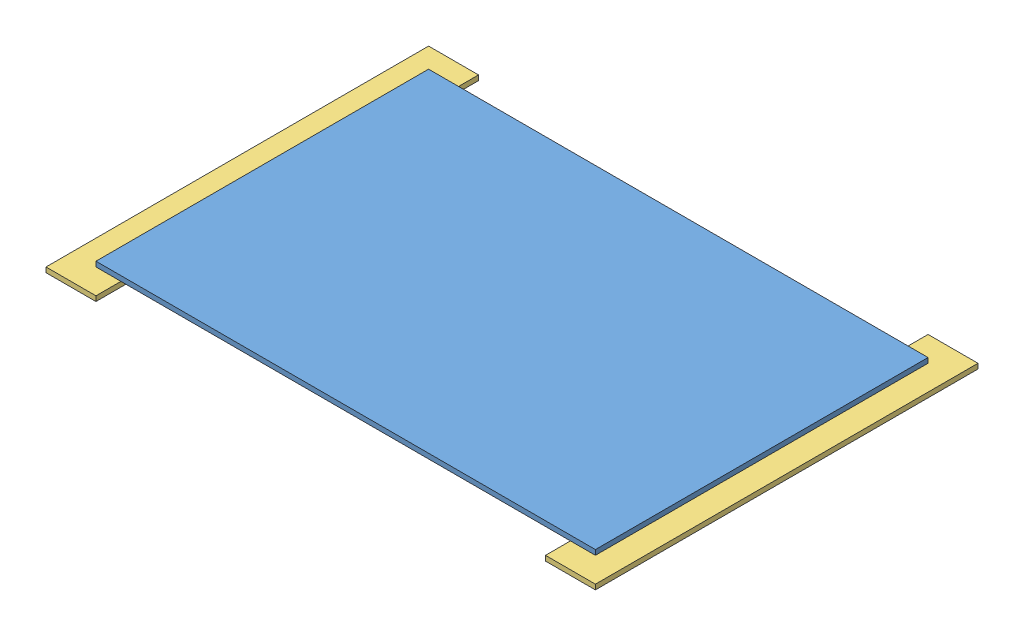
SolidWorks assembly Terrain_9_Partie_5, configuration Default. Lengths in mm.
Overall size (1100 20 766).
4 component instances, 3 part files, 9 mates.
Components (placement in the parent):
- planche_1000x666x10-1: planche_1000x666x10 [Default] at (-501.182 145.1843 231.5907) size (1000 10 666)
- planche_900x100x10-1: planche_900x100x10 [Default] at (-451.182 135.1843 -51.4093) size (900 10 100)
- planche_766x100x10-1: planche_766x100x10 [Default] at (548.818 135.1843 281.5907) x (0 0 -1) z (1 0 0) size (766 10 100)
- planche_766x100x10-2: planche_766x100x10 [Default] at (-451.182 135.1843 281.5907) x (0 0 -1) z (1 0 0) size (766 10 100)
Mates (geometry in assembly coordinates):
- Coïncidente1: coincident anti-aligned: plane of planche_1000x666x10-1 through (-501.182 145.1843 -434.4093) normal (0 -1 0); plane of planche_900x100x10-1 through (-451.182 145.1843 -151.4093) normal (0 1 0)
- Distance1: distance = 50 mm aligned: plane of planche_900x100x10-1 through (448.818 145.1843 -51.4093) normal (1 0 0); plane of planche_1000x666x10-1 through (498.818 155.1843 231.5907) normal (1 0 0)
- Distance4: distance = 383 mm anti-aligned: plane of planche_900x100x10-1 through (-451.182 145.1843 -151.4093) normal (0 0 -1); plane of planche_1000x666x10-1 through (-501.182 155.1843 231.5907) normal (0 0 1)
- Coïncidente2: coincident anti-aligned: plane of planche_1000x666x10-1 through (-501.182 145.1843 -434.4093) normal (0 -1 0); plane of ? through (448.818 145.1843 217.9054) normal (0 1 0)
- Coïncidente3: coincident anti-aligned: plane of planche_1000x666x10-1 through (-501.182 145.1843 -434.4093) normal (0 -1 0); plane of planche_766x100x10-2 through (-551.182 145.1843 281.5907) normal (0 1 0)
- Coïncidente4: coincident anti-aligned: plane of planche_900x100x10-1 through (448.818 145.1843 -51.4093) normal (1 0 0); plane of ? through (448.818 145.1843 217.9054) normal (-1 0 0)
- Coïncidente5: coincident anti-aligned: plane of planche_900x100x10-1 through (-451.182 145.1843 -51.4093) normal (-1 0 0); plane of planche_766x100x10-2 through (-451.182 145.1843 281.5907) normal (1 0 0)
- Distance5: distance = 50 mm aligned: plane of planche_766x100x10-2 through (-451.182 145.1843 281.5907) normal (0 0 1); plane of planche_1000x666x10-1 through (-501.182 155.1843 231.5907) normal (0 0 1)
- Coïncidente7: coincident aligned: plane of ? through (548.818 145.1843 217.9054) normal (0 0 1); plane of planche_766x100x10-2 through (-451.182 145.1843 281.5907) normal (0 0 1)
